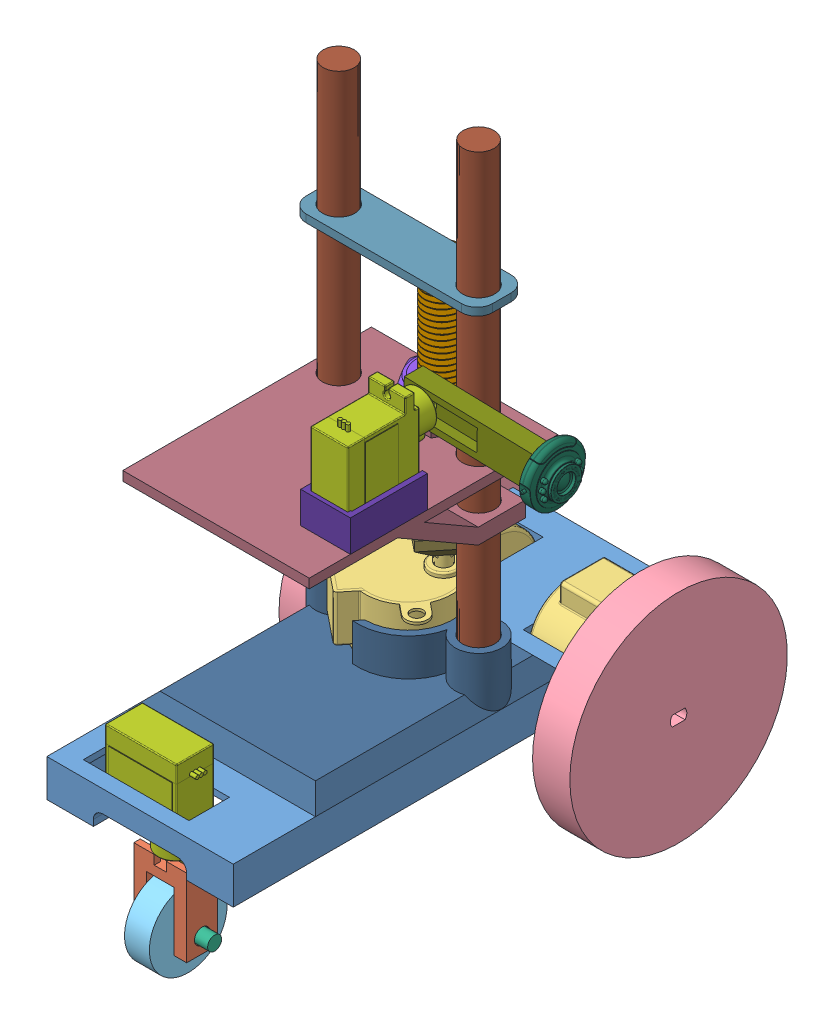
SolidWorks assembly fullAssem, configuration Default. Lengths in mm.
Overall size (112.9 204 162.5).
24 component instances, 17 part files, 3 mates.
Components (placement in the parent):
- Chassis assembly-1: Chassis assembly [Default] at (-180 -15.0412 -20.4391) x (1 0 0) z (0 0 -1) size (93.6 70 162.5)
  - chassis-1: chassis [Default] at (150 -8.0412 -86.8763) size (67.4 12 150)
  - wheel holder-1: wheel holder [Default] at (180 21.9588 -80.3763) x (-1 0 0) z (0 0 1) size (17 25 10)
  - 28BYJ48-1: 28BYJ48 [默认] at (149.2 -4.0412 39.6237) x (0 0 -1) z (1 0 0) size (42 32 29)
  - 28BYJ48-2: 28BYJ48 [默认] at (210.8 -4.0412 39.6237) x (0 0 1) z (-1 0 0) size (42 32 29)
  - stepper wheel-1: stepper wheel [Default] at (145.2 3.9588 39.6237) size (12 70 70)
  - stepper wheel-2: stepper wheel [Default] at (226.8 3.9588 39.6237) size (12 70 70)
  - servo wheel-1: servo wheel [Default] at (176 26.4588 -75.3763) size (8 25 25)
  - servo shaft-1: servo shaft [Default] at (171.5 26.4588 -75.3763) x (1 0 0) z (0 -0.284834 0.958577) size (21 4.5 4.5)
  - Servo-MG90S-1: Servo-MG90S [Default] at (174.75 -23.0412 -75.3763) size (32.2 32.5 12.4)
- upDownPlatform-1: upDownPlatform [Default] at origin size (96.1 155 86.09)
  - 90592A028_STEEL HEX NUT-1: 90592A028_STEEL HEX NUT [90592A028] at (5.0301 67.4883 -26.2208) x (0.866025 0 0.5) z (-0.5 0 0.866025) size (19 11.37 21.94)
  - ratthamnoonPrakitpong_1_threadedRod-1: ratthamnoonPrakitpong_1_threadedRod [1078N44] at (5.0301 69.5 -26.2208) x (0 -1 0) z (-0.358551 0 0.93351) size (76.86 12.46 12.62)
  - 28BYJ48-1: 28BYJ48 [默认] at (0 19 -20) x (-0.777594 0 -0.628767) z (0 -1 0) size (42 32 29)
  - base-1: base [Default] at origin size (60 17 80)
  - rod-1: rod [Default] at (-22.5 0 -20) x (-0.241393 0 0.970427) z (-0.970427 0 -0.241393) size (10 150 10)
  - rod-2: rod [Default] at (22.5 0 -20) size (10 150 10)
  - leadScrewMount-1: leadScrewMount [Default] at (5.0301 29 -26.2208) x (0.777594 0 0.628767) z (-0.628767 0 0.777594) size (15 8 15)
  - cameraMount-1: cameraMount [Default] at (0 59.4883 2) size (60 21 80)
  - rodCap-1: rodCap [Default] at (0 107 -20) size (60 2.5 16)
  - Webcam-1: Webcam [Défaut] at (61.5361 83.3406 -4.95) x (0 0 -1) z (0.999649 -0.026489 0) size (20 18.82 9.8)
  - Servo-MG90S-1: Servo-MG90S [Default] at (22 79.1383 27.55) x (0 1 0) z (-1 0 0) size (32.2 32.5 12.4)
  - servo extension-1: servo extension [Default] at (16.6476 90.032 -4.95) x (0.999649 -0.026489 0) z (-0.026489 -0.999649 0) size (43.55 6 11)
  - stage servo mount-1: stage servo mount [Default] at (14 62.4883 28.75) x (0 0 -1) z (1 0 0) size (24.8 10.15 16)
Mates (geometry in assembly coordinates):
- Coincident1: coordinate: point of upDownPlatform-1
- Coincident3: coincident aligned: line of Chassis assembly-1 through (-30 -5 40) axis (1 0 0); line of upDownPlatform-1/base-1 through (-30 -5 40) axis (1 0 0)
- Coincident4: coincident anti-aligned: line of Chassis assembly-1 through (30 -5 -40) axis (0 0 1); line of upDownPlatform-1/base-1 through (30 -5 40) axis (0 0 -1)
